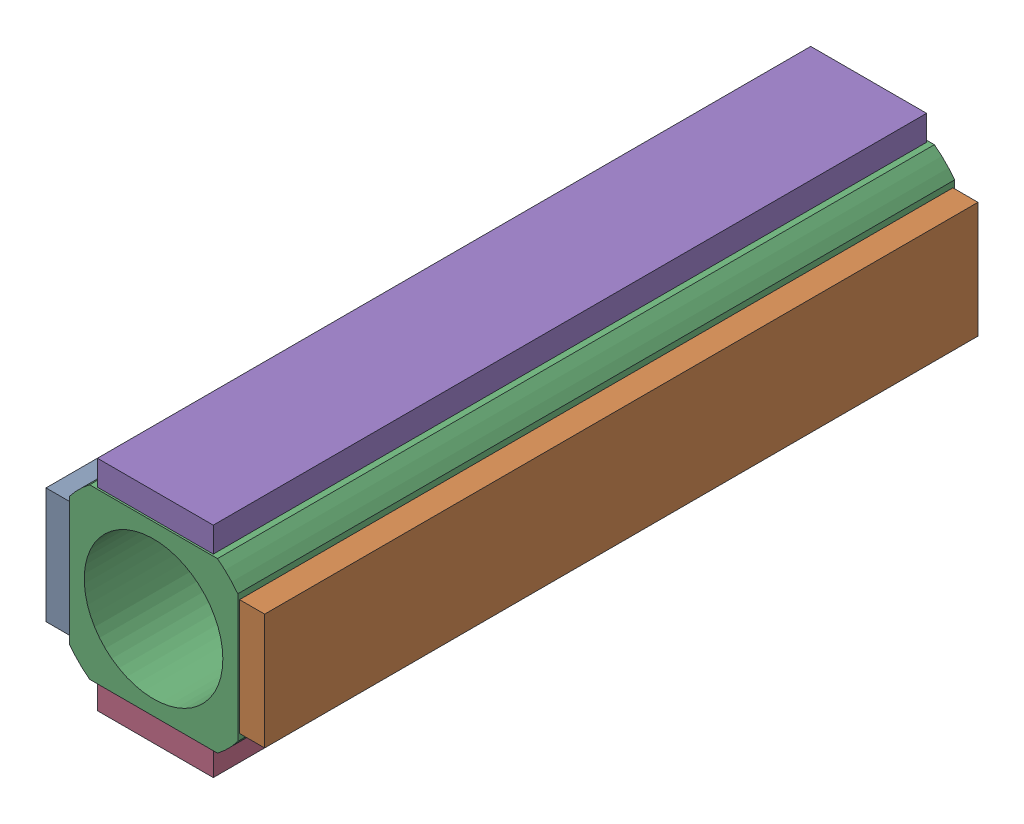
SolidWorks assembly 02356-3-0000, configuration Default. Lengths in mm.
Overall size (1.83 1.83 6).
5 component instances, 2 part files, 0 mates.
Components (placement in the parent):
- 02094-0-0000-1: 02094-0-0000 [Default] at (53.8621 -453.2709 1) x (0 -1 0) z (-1 0 0) size (0.97 5.97 0.21)
- 02094-0-0000-2: 02094-0-0000 [Default] at (55.2721 -453.2709 1) x (0 -1 0) z (1 0 0) size (0.97 5.97 0.21)
- 01594-0-0000_drawing view-1: 01594-0-0000_drawing view [Default] at (54.5671 -453.2709 1) size (1.41 1.41 6)
- 02094-0-0000-3: 02094-0-0000 [Default] at (54.5671 -453.9759 1) x (1 0 0) z (0 -1 0) size (0.97 5.97 0.21)
- 02094-0-0000-4: 02094-0-0000 [Default] at (54.5671 -452.5659 1) x (1 0 0) z (0 1 0) size (0.97 5.97 0.21)
